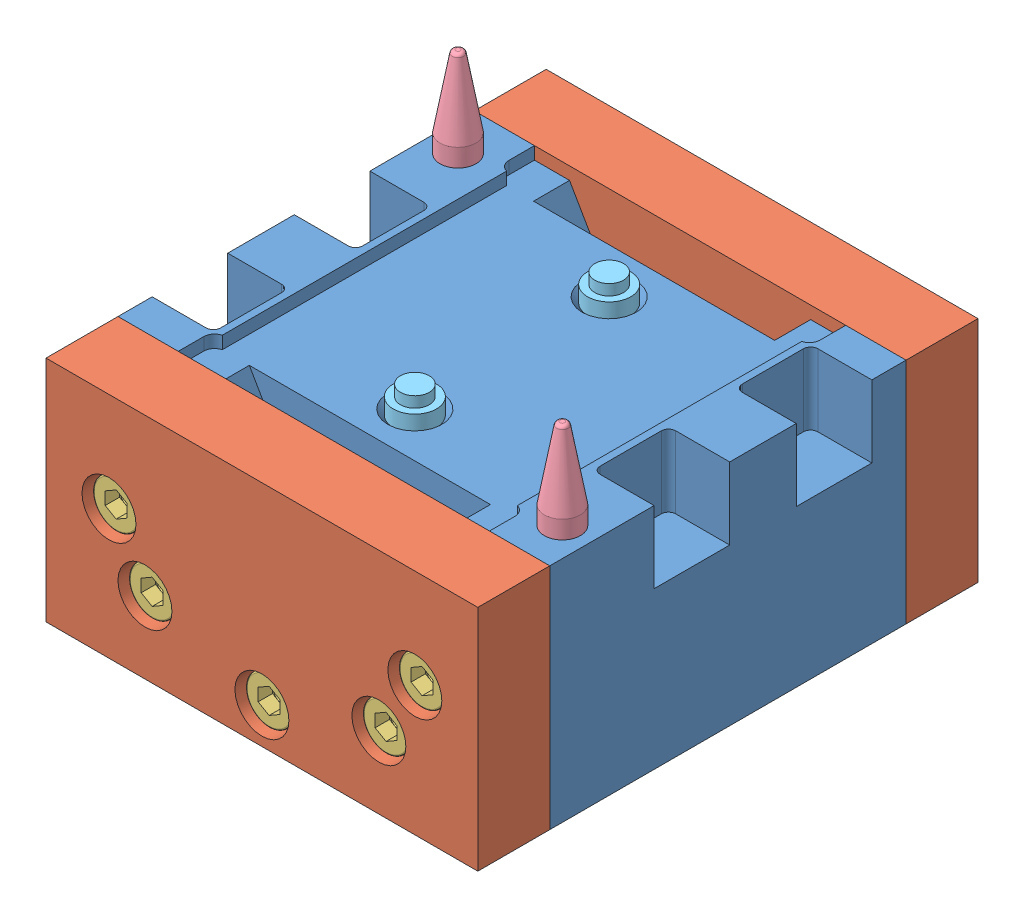
SolidWorks assembly  ЧМВ1.01.00 - Сборка Матрицы, configuration По умолчанию. Lengths in mm.
Overall size (120 88.5 139).
19 component instances, 5 part files, 34 mates.
Components (placement in the parent):
- ЧМВ1.01.02 - Матрица-1: ЧМВ1.01.02 - Матрица [Default] at origin size (120 63.5 99)
- ЧМВ1.01.02 - Боковина Пресс-формы-1: ЧМВ1.01.02 - Боковина Пресс-формы [По умолчанию] at (0 36.1757 49.5) size (120 63.5 20)
- ЧМВ1.01.02 - Боковина Пресс-формы-3: ЧМВ1.01.02 - Боковина Пресс-формы [По умолчанию] at (0 36.1757 -49.5) x (-1 0 0) z (0 0 -1) size (120 63.5 20)
- socket head cap screw_iso-1: socket head cap screw_iso [ISO 4762 M8 x 16 - 16N] at (-42.5 36 -67.5) x (0 0 1) z (-1 0 0) size (24 13 13)
- socket head cap screw_iso-2: socket head cap screw_iso [ISO 4762 M8 x 16 - 16N] at (-32.5 20 -67.5) x (0 0 1) z (-1 0 0) size (24 13 13)
- socket head cap screw_iso-3: socket head cap screw_iso [ISO 4762 M8 x 16 - 16N] at (0 10 -67.5) x (0 0 1) z (-1 0 0) size (24 13 13)
- socket head cap screw_iso-4: socket head cap screw_iso [ISO 4762 M8 x 16 - 16N] at (32.5 20 -67.5) x (0 0 1) z (-1 0 0) size (24 13 13)
- socket head cap screw_iso-5: socket head cap screw_iso [ISO 4762 M8 x 16 - 16N] at (42.5 36 -67.5) x (0 0 1) z (-1 0 0) size (24 13 13)
- socket head cap screw_iso-6: socket head cap screw_iso [ISO 4762 M8 x 16 - 16N] at (42.5 36 67.5) x (0 0 -1) z (1 0 0) size (24 13 13)
- socket head cap screw_iso-7: socket head cap screw_iso [ISO 4762 M8 x 16 - 16N] at (32.5 20 67.5) x (0 0 -1) z (1 0 0) size (24 13 13)
- socket head cap screw_iso-10: socket head cap screw_iso [ISO 4762 M8 x 16 - 16N] at (-42.5 36 67.5) x (0 0 -1) z (1 0 0) size (24 13 13)
- socket head cap screw_iso-8: socket head cap screw_iso [ISO 4762 M8 x 16 - 16N] at (0 10 67.5) x (0 0 -1) z (1 0 0) size (24 13 13)
- socket head cap screw_iso-9: socket head cap screw_iso [ISO 4762 M8 x 16 - 16N] at (-32.5 20 67.5) x (0 0 -1) z (1 0 0) size (24 13 13)
- socket head cap screw_iso-11: socket head cap screw_iso [ISO 4762 M8 x 16 - 16N] at (-32.5 20 67.5) x (0 0 -1) z (1 0 0) size (24 13 13)
- socket head cap screw_iso-12: socket head cap screw_iso [ISO 4762 M8 x 16 - 16N] at (-42.5 36 67.5) x (0 0 -1) z (1 0 0) size (24 13 13)
- ЧМВ1.01.03 - Направляющая-1: ЧМВ1.01.03 - Направляющая [Default] at (52 33.5 38) x (0 1 0) z (-0.458497 0 -0.888696) size (55 10 10)
- ЧМВ1.01.03 - Направляющая-3: ЧМВ1.01.03 - Направляющая [Default] at (-51.997 33.5 -37) x (0 1 0) z (-0.61776 0 -0.786366) size (55 10 10)
- ЧМВ1.01.04 - Подставка-2: ЧМВ1.01.04 - Подставка [По умолчанию] at (0 48 -27) x (0.955678 0 -0.294415) z (0 -1 0) size (12 12 36)
- ЧМВ1.01.04 - Подставка-3: ЧМВ1.01.04 - Подставка [По умолчанию] at (0 48 27) x (0.972927 0 -0.231111) z (0 -1 0) size (12 12 36)
Mates (geometry in assembly coordinates):
- Совпадение1: coincident anti-aligned: plane of Матрица-1 through (60 63.5 49.5) normal (0 0 1); plane of Боковина Пресс-формы.-1 through (0 36.1757 49.5) normal (0 0 -1)
- Концентричный1: concentric anti-aligned: cylinder of Матрица-1 through (42.5 36 49.5) axis (0 0 1) radius 3.5; cylinder of Боковина Пресс-формы.-1 through (42.5 36 69.5) axis (0 0 -1) radius 4.25
- Концентричный2: concentric anti-aligned: cylinder of Матрица-1 through (-42.5 36 49.5) axis (0 0 1) radius 3.5; cylinder of Боковина Пресс-формы.-1 through (-42.5 36 69.5) axis (0 0 -1) radius 4.25
- Совпадение3: coincident anti-aligned: plane of Матрица-1 through (60 63.5 -49.5) normal (0 0 -1); plane of Боковина Пресс-формы.-3 through (0 36.1757 -49.5) normal (0 0 1)
- Концентричный3: concentric anti-aligned: cylinder of Матрица-1 through (42.5 36 -49.5) axis (0 0 -1) radius 3.5; cylinder of Боковина Пресс-формы.-3 through (42.5 36 -69.5) axis (0 0 1) radius 4.25
- Концентричный4: concentric anti-aligned: cylinder of Матрица-1 through (-42.5 36 -49.5) axis (0 0 -1) radius 3.5; cylinder of Боковина Пресс-формы.-3 through (-42.5 36 -69.5) axis (0 0 1) radius 4.25
- Концентричный5: concentric anti-aligned: cylinder of Боковина Пресс-формы.-3 through (-42.5 36 -69.5) axis (0 0 1) radius 4.25; cylinder of socket head cap screw_iso-1 through (-42.5 36 -99.25) axis (0 0 -1) radius 6.5
- Совпадение4: coincident anti-aligned: plane of Боковина Пресс-формы.-3 through (-42.5 36 -59.5) normal (0 0 -1); plane of socket head cap screw_iso-1 through (-42.5 42.5 -59.5) normal (0 0 1)
- Концентричный6: concentric aligned: cylinder of Боковина Пресс-формы.-3 through (-32.5 20 -59.5) axis (0 0 -1) radius 7.5; cylinder of socket head cap screw_iso-2 through (-32.5 20 -99.25) axis (0 0 -1) radius 6.5
- Совпадение5: coincident anti-aligned: plane of Боковина Пресс-формы.-3 through (-32.5 20 -59.5) normal (0 0 -1); plane of socket head cap screw_iso-2 through (-32.5 26.5 -59.5) normal (0 0 1)
- Концентричный7: concentric anti-aligned: cylinder of Боковина Пресс-формы.-3 through (0 10 -69.5) axis (0 0 1) radius 4.25; cylinder of socket head cap screw_iso-3 through (0 10 -99.25) axis (0 0 -1) radius 6.5
- Совпадение6: coincident anti-aligned: plane of Боковина Пресс-формы.-3 through (0 10 -59.5) normal (0 0 -1); plane of socket head cap screw_iso-3 through (0 16.5 -59.5) normal (0 0 1)
- Концентричный8: concentric anti-aligned: cylinder of Боковина Пресс-формы.-3 through (32.5 20 -69.5) axis (0 0 1) radius 4.25; cylinder of socket head cap screw_iso-4 through (32.5 20 -99.25) axis (0 0 -1) radius 6.5
- Совпадение7: coincident anti-aligned: plane of Боковина Пресс-формы.-3 through (32.5 20 -59.5) normal (0 0 -1); plane of socket head cap screw_iso-4 through (32.5 26.5 -59.5) normal (0 0 1)
- Концентричный9: concentric aligned: cylinder of Боковина Пресс-формы.-3 through (42.5 36 -59.5) axis (0 0 -1) radius 7.5; cylinder of socket head cap screw_iso-5 through (42.5 36 -99.25) axis (0 0 -1) radius 6.5
- Совпадение8: coincident anti-aligned: plane of Боковина Пресс-формы.-3 through (42.5 36 -59.5) normal (0 0 -1); plane of socket head cap screw_iso-5 through (42.5 42.5 -59.5) normal (0 0 1)
- Концентричный10: concentric anti-aligned: cylinder of Боковина Пресс-формы.-1 through (42.5 36 69.5) axis (0 0 -1) radius 4.25; cylinder of socket head cap screw_iso-6 through (42.5 36 99.25) axis (0 0 1) radius 6.5
- Совпадение9: coincident anti-aligned: plane of Боковина Пресс-формы.-1 through (42.5 36 59.5) normal (0 0 1); plane of socket head cap screw_iso-6 through (42.5 42.5 59.5) normal (0 0 -1)
- Концентричный11: concentric aligned: cylinder of Боковина Пресс-формы.-1 through (32.5 20 59.5) axis (0 0 1) radius 7.5; cylinder of socket head cap screw_iso-7 through (32.5 20 99.25) axis (0 0 1) radius 6.5
- Совпадение10: coincident anti-aligned: plane of Боковина Пресс-формы.-1 through (32.5 20 59.5) normal (0 0 1); plane of socket head cap screw_iso-7 through (32.5 26.5 59.5) normal (0 0 -1)
- Концентричный12: concentric anti-aligned: cylinder of Боковина Пресс-формы.-1 through (0 10 69.5) axis (0 0 -1) radius 4.25; cylinder of socket head cap screw_iso-8 through (0 10 99.25) axis (0 0 1) radius 6.5
- Совпадение11: coincident anti-aligned: plane of Боковина Пресс-формы.-1 through (0 10 59.5) normal (0 0 1); plane of socket head cap screw_iso-8 through (0 16.5 59.5) normal (0 0 -1)
- Концентричный13: concentric aligned: cylinder of Боковина Пресс-формы.-1 through (-32.5 20 59.5) axis (0 0 1) radius 7.5; cylinder of socket head cap screw_iso-9 through (-32.5 20 99.25) axis (0 0 1) radius 6.5
- Совпадение12: coincident anti-aligned: plane of Боковина Пресс-формы.-1 through (-32.5 20 59.5) normal (0 0 1); plane of socket head cap screw_iso-9 through (-32.5 26.5 59.5) normal (0 0 -1)
- Концентричный14: concentric aligned: cylinder of Боковина Пресс-формы.-1 through (-42.5 36 59.5) axis (0 0 1) radius 7.5; cylinder of socket head cap screw_iso-10 through (-42.5 36 99.25) axis (0 0 1) radius 6.5
- Совпадение13: coincident anti-aligned: plane of Боковина Пресс-формы.-1 through (-42.5 36 59.5) normal (0 0 1); plane of socket head cap screw_iso-10 through (-42.5 42.5 59.5) normal (0 0 -1)
- Концентричный15: concentric anti-aligned: cylinder of Матрица-1 through (52 33.5 38) axis (0 1 0) radius 5; cylinder of Направляющая-1 through (52 33.5 38) axis (0 -1 0) radius 5
- Совпадение14: coincident anti-aligned: plane of Матрица-1 through (52 33.5 38) normal (0 1 0); circle of Направляющая-1
- Концентричный17: concentric anti-aligned: cylinder of Матрица-1 through (-51.997 33.5 -37) axis (0 1 0) radius 5; cylinder of Направляющая-3 through (-51.997 33.5 -37) axis (0 -1 0) radius 5
- Совпадение17: coincident anti-aligned: plane of Матрица-1 through (-51.997 33.5 -37) normal (0 1 0); circle of Направляющая-3
- Концентричный20: concentric anti-aligned: cylinder of Матрица-1 through (0 30 -27) axis (0 1 0) radius 6; cylinder of Подставка-2 through (0 30 -27) axis (0 -1 0) radius 6
- Концентричный21: concentric anti-aligned: cylinder of Матрица-1 through (0 30 27) axis (0 1 0) radius 6; cylinder of Подставка-3 through (0 30 27) axis (0 -1 0) radius 6
- Совпадение20: coincident anti-aligned: plane of Матрица-1 through (0 30 0) normal (0 1 0); plane of Подставка-3 through (0 30 27) normal (0 -1 0)
- Совпадение21: coincident anti-aligned: plane of Матрица-1 through (0 30 0) normal (0 1 0); plane of Подставка-2 through (0 30 -27) normal (0 -1 0)
